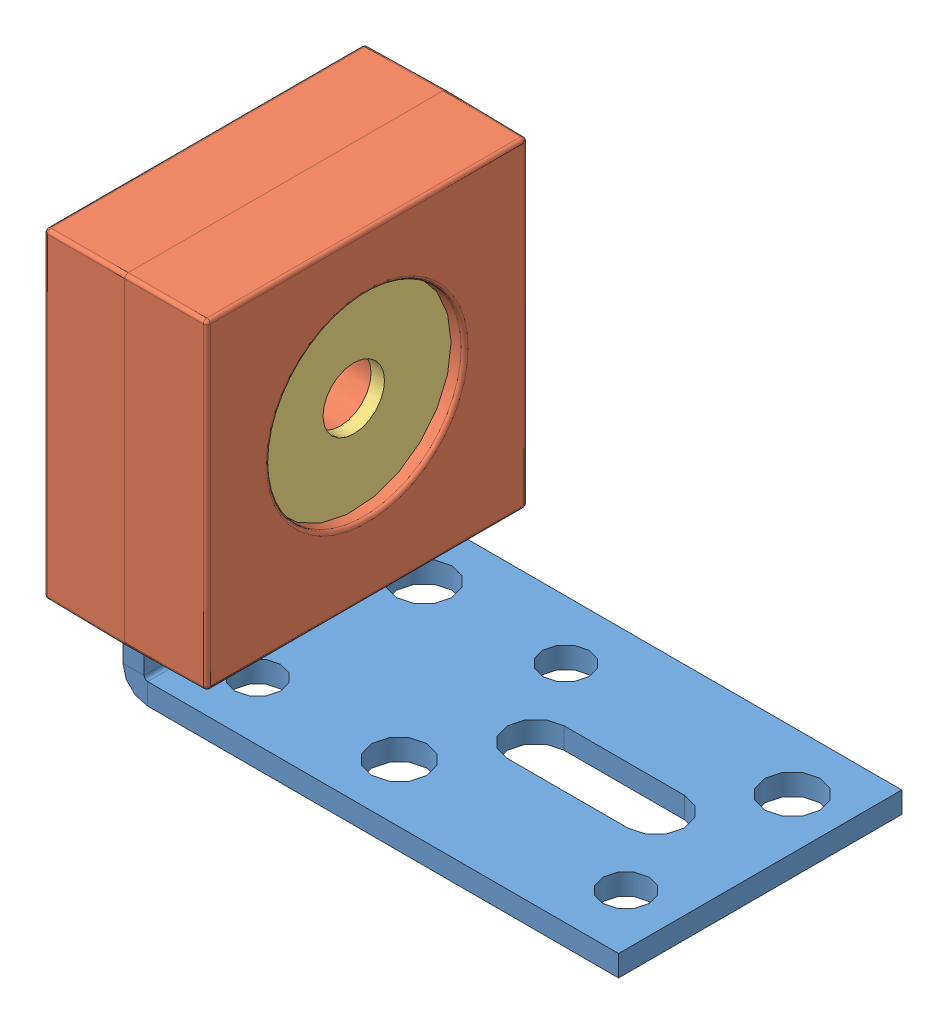
SolidWorks assembly 993685, configuration Default. Lengths in mm.
Overall size (78.5 53.9 45.5).
3 component instances, 3 part files, 5 mates.
Components (placement in the parent):
- 993685-1: 993685 [Default] at (-12.8884 7.5756 58.5374) size (70 50 40)
- 注塑-1: 注塑 [Default] at (-9.8884 38.5483 58.5374) size (23 45.5 45.5)
- 圆铁片-1: 圆铁片 [Default] at (-0.2884 39.7756 58.5374) x (0 1 0) z (0 0 1) size (30 1.9 30)
Mates (geometry in assembly coordinates):
- 同心1: concentric anti-aligned: cylinder of 993685-1 through (-19.8884 39.7756 58.5374) axis (1 0 0) radius 7.25; cone of 注塑-1 through (-9.8884 39.7756 58.5374) axis (-1 0 0)
- 重合1: coincident anti-aligned: plane of 993685-1 through (-9.8884 57.5756 78.5374) normal (1 0 0); plane of 注塑-1 through (-9.8884 38.5483 58.5374) normal (-1 0 0)
- 重合3: coincident anti-aligned: plane of 993685-1 through (-9.3884 10.5756 78.5374) normal (0 0 1); plane of 注塑-1 through (-12.8884 57.5756 78.5374) normal (0 0 -1)
- 重合4: coincident anti-aligned: plane of 注塑-1 through (-2.1884 39.7756 58.5374) normal (1 0 0); plane of 圆铁片-1 through (-2.1884 39.7756 58.5374) normal (-1 0 0)
- 同心2: concentric anti-aligned: cone of 注塑-1 through (-9.8884 39.7756 58.5374) axis (-1 0 0); cylinder of 圆铁片-1 through (-2.1884 39.7756 58.5374) axis (1 0 0) radius 4.35
